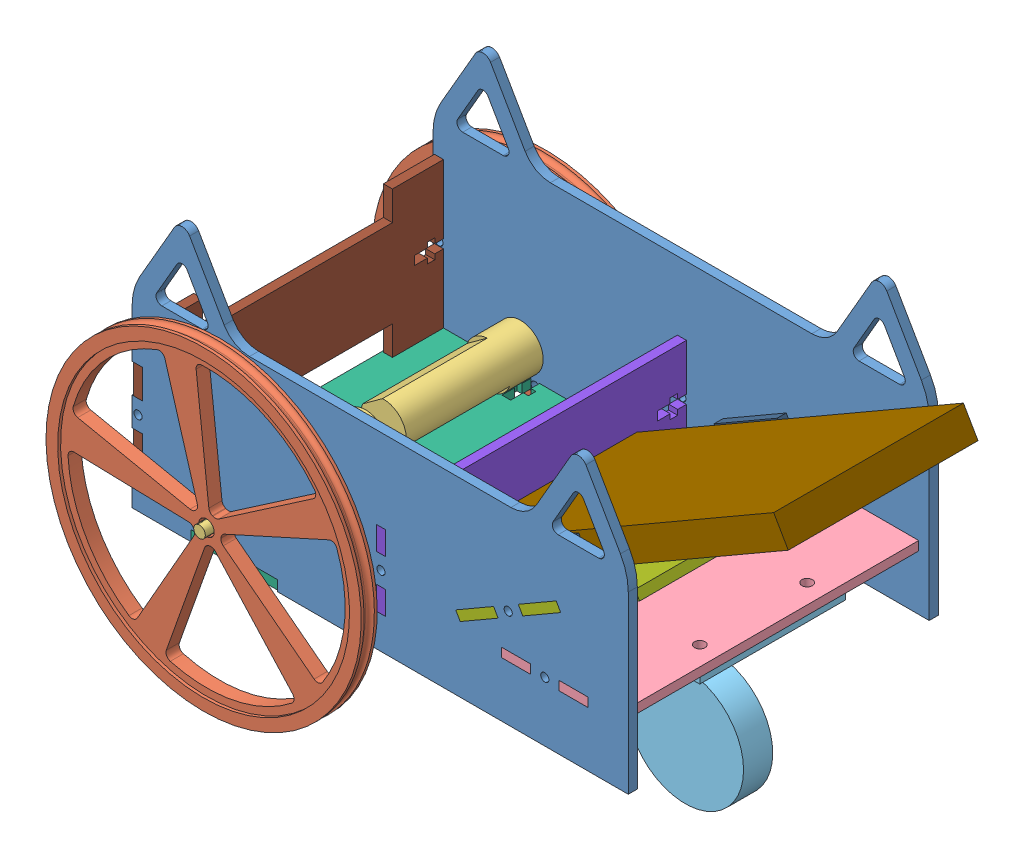
SolidWorks assembly car, configuration 默认. Lengths in mm.
Overall size (248.73 155.6 120).
15 component instances, 11 part files, 41 mates.
Components (placement in the parent):
- sideboard-1: sideboard [默认] at (-2.3598 -47.6791 200) size (170 92 3.1)
- wheel2-1: wheel2 [默认] at (-57.3598 -36.3291 205.85) x (0.980239 0.197819 0) z (0.197819 -0.980239 0) size (108 5.5 108)
- motor-1: motor [默认] at (-57.3598 -36.3291 200) size (15.5 15.5 56.9)
- board_hold_frontwheel-1: board_hold_frontwheel [默认] at (54.0402 -27.2791 150) size (50 3.1 106.2)
- frontwheel-1: frontwheel [默认] at (54.0402 -68.8291 150) size (50 60 50)
- sideboard-2: sideboard [默认] at (-2.3598 -47.6791 96.9) size (170 92 3.1)
- motor-2: motor [默认] at (-57.3598 -36.3291 100) x (0.58842 -0.808555 0) z (0 0 -1) size (15.5 15.5 56.9)
- wheel2-2: wheel2 [默认] at (-57.3598 -36.3291 94.15) x (0.82961 0.558343 0) z (0.558343 -0.82961 0) size (108 5.5 108)
- rearboard-1: rearboard [默认] at (-52.3598 -47.1791 150) size (90 3.1 106.2)
- phoneboard-1: phoneboard [默认] at (42.279 -15.2714 150) x (0.866025 0.5 0) z (0 0 1) size (95 3.1 106.2)
- verboard-1: verboard [默认] at (-0.5322 -23.6202 150) x (0 0 1) z (0 -1 0) size (106.2 3.1 35)
- phone-1: phone [默认] at (60.1333 -1.3836 149.5662) x (0 0 1) z (-0.866025 -0.5 0) size (65 10 130)
- border-1: border [默认] at (38.229 -8.2566 184) x (0.866025 0.5 0) z (0 0 1) size (25 13.1 3.1)
- border-2: border [默认] at (38.229 -8.2566 112.9) x (0.866025 0.5 0) z (0 0 1) size (25 13.1 3.1)
- verrearboard-1: verrearboard [默认] at (-86.8598 -19.0791 150) x (0 -1 0) z (0 0 1) size (50 3.1 106.2)
Mates (geometry in assembly coordinates):
- 平行1: parallel aligned: plane of sideboard-1 through (-67.3598 12.3209 203.1) normal (0 0 1); plane of wheel2-1 through (-57.3598 -36.3291 207.6) normal (0 0 1)
- 同心1: concentric anti-aligned: cylinder of sideboard-1 through (-57.3598 -36.3291 200) axis (0 0 1) radius 2.15; cylinder of motor-1 through (-57.3598 -36.3291 210) axis (0 0 -1) radius 2
- 重合2: coincident anti-aligned: plane of sideboard-1 through (-67.3598 12.3209 200) normal (0 0 -1); plane of motor-1 through (-57.3598 -36.3291 200) normal (0 0 1)
- 同心2: concentric aligned: cylinder of wheel2-1 through (-57.3598 -36.3291 208.6) axis (0 0 -1) radius 2.65; cylinder of motor-1 through (-57.3598 -36.3291 210) axis (0 0 -1) radius 2
- 重合3: coincident anti-aligned: plane of sideboard-1 through (-67.3598 12.3209 203.1) normal (0 0 1); plane of wheel2-1 through (-57.3598 -36.3291 203.1) normal (0 0 -1)
- 重合4: coincident anti-aligned: plane of board_hold_frontwheel-1 through (54.0402 -28.8291 150) normal (0 -1 0); plane of frontwheel-1 through (54.0402 -28.8291 152.5) normal (0 1 0)
- 同心3: concentric anti-aligned: cylinder of frontwheel-1 through (35.6402 -30.8291 131.6) axis (0 1 0) radius 1.8; cylinder of board_hold_frontwheel-1 through (35.6402 -25.7291 131.6) axis (0 -1 0) radius 1.8
- 平行4: parallel aligned: plane of board_hold_frontwheel-1 through (79.0402 -25.7291 150) normal (1 0 0); plane of frontwheel-1 through (79.0402 -30.8291 175) normal (1 0 0)
- 同心4: concentric anti-aligned: cylinder of motor-2 through (-57.3598 -36.3291 90) axis (0 0 1) radius 2; cylinder of wheel2-2 through (-57.3598 -36.3291 96.9) axis (0 0 -1) radius 2.65
- 平行5: parallel aligned: plane of sideboard-1 through (-67.3598 12.3209 203.1) normal (0 0 1); plane of wheel2-2 through (-57.3598 -36.3291 95.9) normal (0 0 1)
- 同心7: concentric aligned: cylinder of sideboard-2 through (-57.3598 -36.3291 96.9) axis (0 0 1) radius 2.15; cylinder of motor-2 through (-57.3598 -36.3291 90) axis (0 0 1) radius 2
- 重合7: coincident anti-aligned: plane of sideboard-2 through (-67.3598 12.3209 100) normal (0 0 1); plane of motor-2 through (-57.3598 -36.3291 100) normal (0 0 -1)
- 重合8: coincident anti-aligned: plane of sideboard-2 through (-67.3598 12.3209 96.9) normal (0 0 -1); plane of wheel2-2 through (-57.3598 -36.3291 96.9) normal (0 0 1)
- 重合9: coincident aligned: plane of sideboard-1 through (82.6402 -47.6791 203.1) normal (0 -1 0); plane of sideboard-2 through (82.6402 -47.6791 100) normal (0 -1 0)
- 重合10: coincident aligned: plane of sideboard-1 through (82.6402 -47.6791 203.1) normal (1 0 0); plane of sideboard-2 through (82.6402 -47.6791 100) normal (1 0 0)
- 平行6: parallel aligned: plane of sideboard-1 through (-67.3598 12.3209 203.1) normal (0 0 1); plane of sideboard-2 through (-67.3598 12.3209 100) normal (0 0 1)
- 重合16: coincident anti-aligned: plane of board_hold_frontwheel-1 through (54.0402 -25.7291 100) normal (0 0 -1); plane of sideboard-2 through (-67.3598 12.3209 100) normal (0 0 1)
- 重合17: coincident anti-aligned: plane of board_hold_frontwheel-1 through (54.0402 -25.7291 150) normal (0 1 0); plane of sideboard-2 through (-2.3598 -25.7291 96.9) normal (0 -1 0)
- 重合18: coincident anti-aligned: plane of board_hold_frontwheel-1 through (68.9152 -25.7291 150) normal (1 0 0); plane of sideboard-2 through (68.9152 -47.6791 96.9) normal (-1 0 0)
- 重合19: coincident anti-aligned: plane of sideboard-1 through (-67.3598 12.3209 200) normal (0 0 -1); plane of phoneboard-1 through (40.729 -12.5867 200) normal (0 0 1)
- 重合20: coincident anti-aligned: plane of sideboard-1 through (-5.2331 -42.7025 200) normal (-0.5 0.866025 0); plane of phoneboard-1 through (42.279 -15.2714 150) normal (0.5 -0.866025 0)
- 重合21: coincident anti-aligned: plane of sideboard-1 through (27.9399 -30.1855 200) normal (0.866025 0.5 0); plane of phoneboard-1 through (23.5167 -22.5242 150) normal (-0.866025 -0.5 0)
- 重合22: coincident anti-aligned: plane of sideboard-1 through (-67.3598 12.3209 200) normal (0 0 -1); plane of verboard-1 through (-3.6322 -23.6202 200) normal (0 0 1)
- 重合28: coincident anti-aligned: plane of sideboard-1 through (-2.3598 -18.7452 200) normal (0 1 0); plane of verboard-1 through (-3.6322 -18.7452 150) normal (0 -1 0)
- 重合29: coincident anti-aligned: plane of sideboard-1 through (-3.6322 -47.6791 200) normal (1 0 0); plane of verboard-1 through (-3.6322 -23.6202 150) normal (-1 0 0)
- 重合30: coincident anti-aligned: plane of phoneboard-1 through (40.729 -12.5867 150) normal (-0.5 0.866025 0); plane of phone-1 through (60.1333 -1.3836 149.5662) normal (0.5 -0.866025 0)
- 平行9: parallel aligned: plane of phoneboard-1 through (81.8652 11.1633 150) normal (0.866025 0.5 0); plane of phone-1 through (111.4249 39.7766 117.0662) normal (0.866025 0.5 0)
- 平行10: parallel aligned: plane of sideboard-1 through (-67.3598 12.3209 203.1) normal (0 0 1); plane of phone-1 through (-1.1584 -25.2234 182.0662) normal (0 0 1)
- 重合33: coincident anti-aligned: plane of phoneboard-1 through (32.5017 -17.3367 150) normal (0.866025 0.5 0); plane of border-1 through (30.0017 -13.0066 187.1) normal (-0.866025 -0.5 0)
- 重合34: coincident anti-aligned: plane of phoneboard-1 through (40.729 -12.5867 150) normal (-0.5 0.866025 0); plane of border-1 through (40.729 -12.5867 187.1) normal (0.5 -0.866025 0)
- 重合35: coincident anti-aligned: plane of phoneboard-1 through (40.729 -12.5867 187.1) normal (0 0 -1); plane of border-1 through (38.229 -8.2566 187.1) normal (0 0 1)
- 重合36: coincident anti-aligned: plane of phoneboard-1 through (40.729 -12.5867 116) normal (0 0 -1); plane of border-2 through (38.229 -8.2566 116) normal (0 0 1)
- 重合37: coincident anti-aligned: plane of phoneboard-1 through (32.5017 -17.3367 150) normal (0.866025 0.5 0); plane of border-2 through (30.0017 -13.0066 116) normal (-0.866025 -0.5 0)
- 重合38: coincident anti-aligned: plane of phoneboard-1 through (40.729 -12.5867 150) normal (-0.5 0.866025 0); plane of border-2 through (40.729 -12.5867 116) normal (0.5 -0.866025 0)
- 重合39: coincident anti-aligned: plane of sideboard-2 through (-67.3598 12.3209 100) normal (0 0 1); plane of rearboard-1 through (-52.3598 -44.0791 100) normal (0 0 -1)
- 重合41: coincident anti-aligned: plane of sideboard-2 through (-2.3598 -44.0791 96.9) normal (0 -1 0); plane of rearboard-1 through (-52.3598 -44.0791 150) normal (0 1 0)
- 重合42: coincident anti-aligned: plane of sideboard-2 through (-83.7598 -47.6791 96.9) normal (-1 0 0); plane of verrearboard-1 through (-83.7598 -19.0791 150) normal (1 0 0)
- 重合43: coincident anti-aligned: plane of sideboard-2 through (-67.3598 12.3209 100) normal (0 0 1); plane of verrearboard-1 through (-83.7598 -19.0791 100) normal (0 0 -1)
- 重合44: coincident anti-aligned: plane of sideboard-2 through (-2.3598 -14.2041 96.9) normal (0 1 0); plane of verrearboard-1 through (-83.7598 -14.2041 150) normal (0 -1 0)
- 重合46: coincident anti-aligned: plane of sideboard-2 through (-67.2348 -47.6791 96.9) normal (1 0 0); plane of rearboard-1 through (-67.2348 -44.0791 150) normal (-1 0 0)
- 重合47: coincident anti-aligned: plane of sideboard-1 through (-67.3598 12.3209 200) normal (0 0 -1); plane of verrearboard-1 through (-83.7598 -19.0791 200) normal (0 0 1)
